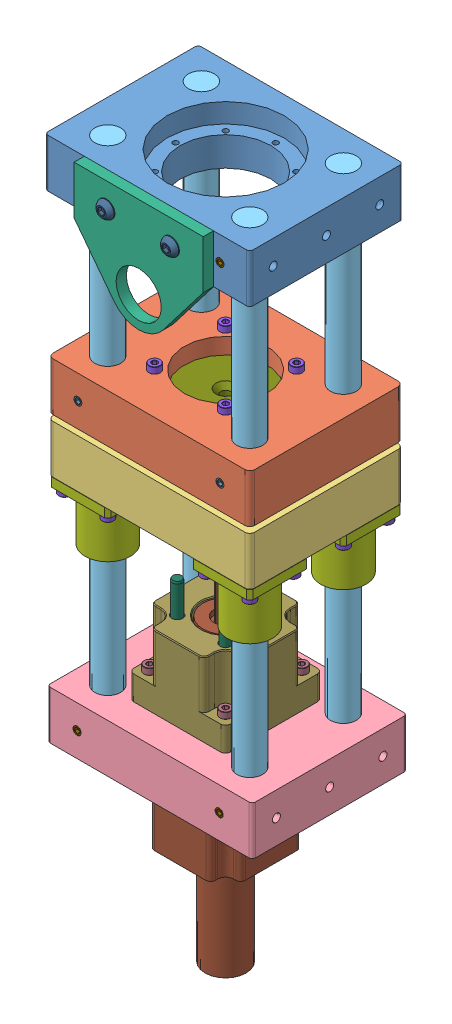
SolidWorks assembly 002 - Plate Assembly, configuration Default. Lengths in mm.
Overall size (129 435.72 106.38).
66 component instances, 16 part files, 53 mates.
Components (placement in the parent):
- 002-101 - Motor Plate-1: 002-101 - Motor Plate [Default] at (39.4552 68.0685 91.2976) size (127 30 95)
- 002-102 - Fixed Mold Plate-1: 002-102 - Fixed Mold Plate [Default] at (39.4552 -20.3315 91.2976) x (-1 0 0) z (0 0 1) size (125 30 95)
- 002-103 - Moving Mold Plate-1: 002-103 - Moving Mold Plate [Default] at (39.4552 -53.9039 91.2976) x (-1 0 0) z (0 0 1) size (125 30 95)
- 002-104 - Actuator Plate-1: 002-104 - Actuator Plate [Default] at (39.4552 -226.9315 91.2976) size (127 30 96)
- SP - 16x295mm Rail - Phidgets LMN4002_0-1: SP - 16x295mm Rail - Phidgets LMN4002_0 [Default] at (83.4552 -64.4315 120.2976) x (1 0 0) z (0 -1 0) size (16 16 325)
- 002-105 - Hopper Bracket-1: 002-105 - Hopper Bracket [Default] at (39.4552 83.0685 145.1476) x (1 0 0) z (0 1 0) size (80 6.35 69.95)
- SP - Bearing LMK16UU - Phidgets LMN4219_0-1: SP - Bearing LMK16UU - Phidgets LMN4219_0 [Default] at (83.4552 -83.9039 120.2976) x (0 0 -1) z (-1 0 0) size (37 37 37)
- SP - M4x12 SHCS - McMaster-Carr 91290A148-1: SP - M4x12 SHCS - McMaster-Carr 91290A148 [91290A148] at (96.8902 -77.9039 133.7326) x (1 0 0) z (0 1 0) size (7 7 16.33)
- SP - M4x12 SHCS - McMaster-Carr 91290A148-2: SP - M4x12 SHCS - McMaster-Carr 91290A148 [91290A148] at (96.8902 -77.9039 106.8626) x (1 0 0) z (0 1 0) size (7 7 16.33)
- SP - M4x12 SHCS - McMaster-Carr 91290A148-3: SP - M4x12 SHCS - McMaster-Carr 91290A148 [91290A148] at (70.0201 -77.9039 133.7326) x (1 0 0) z (0 1 0) size (7 7 16.33)
- SP - M4x12 SHCS - McMaster-Carr 91290A148-4: SP - M4x12 SHCS - McMaster-Carr 91290A148 [91290A148] at (70.0201 -77.9039 106.8626) x (1 0 0) z (0 1 0) size (7 7 16.33)
- SP - M6x10 CPSS - McMaster-Carr 91390A128-1: SP - M6x10 CPSS - McMaster-Carr 91390A128 [91390A128] at (83.4552 -211.9315 134.7915) size (6.22 6.16 11)
- SP - M6x10 CPSS - McMaster-Carr 91390A128-2: SP - M6x10 CPSS - McMaster-Carr 91390A128 [91390A128] at (83.4552 83.0685 134.2915) size (6.22 6.16 11)
- SP - M6x14 BHCS - McMaster-Carr 91239A319-1: SP - M6x14 BHCS - McMaster-Carr 91239A319 [91239A319] at (59.4552 83.0685 148.4476) size (10.5 10.5 17.89)
- SP - M6x14 BHCS - McMaster-Carr 91239A319-2: SP - M6x14 BHCS - McMaster-Carr 91239A319 [91239A319] at (19.4552 83.0685 148.4476) x (-1 0 0) z (0 0 1) size (10.5 10.5 17.89)
- SP - M6x10 CPSS - McMaster-Carr 91390A128-3: SP - M6x10 CPSS - McMaster-Carr 91390A128 [91390A128] at (-4.5448 83.0865 134.2915) x (-1 0 0) z (0 0 1) size (6.22 6.16 11)
- SP - Bearing LMK16UU - Phidgets LMN4219_0-2: SP - Bearing LMK16UU - Phidgets LMN4219_0 [Default] at (-4.5448 -83.9039 120.2976) x (0 0 -1) z (-1 0 0) size (37 37 37)
- SP - M4x12 SHCS - McMaster-Carr 91290A148-5: SP - M4x12 SHCS - McMaster-Carr 91290A148 [91290A148] at (-17.9799 -77.9039 133.7326) x (-1 0 0) z (0 1 0) size (7 7 16.33)
- SP - M4x12 SHCS - McMaster-Carr 91290A148-6: SP - M4x12 SHCS - McMaster-Carr 91290A148 [91290A148] at (-17.9799 -77.9039 106.8626) x (-1 0 0) z (0 1 0) size (7 7 16.33)
- SP - M4x12 SHCS - McMaster-Carr 91290A148-7: SP - M4x12 SHCS - McMaster-Carr 91290A148 [91290A148] at (8.8902 -77.9039 133.7326) x (-1 0 0) z (0 1 0) size (7 7 16.33)
- SP - M4x12 SHCS - McMaster-Carr 91290A148-8: SP - M4x12 SHCS - McMaster-Carr 91290A148 [91290A148] at (8.8902 -77.9039 106.8626) x (-1 0 0) z (0 1 0) size (7 7 16.33)
- SP - M6x10 CPSS - McMaster-Carr 91390A128-4: SP - M6x10 CPSS - McMaster-Carr 91390A128 [91390A128] at (-4.5448 -211.9135 134.7915) x (-1 0 0) z (0 0 1) size (6.22 6.16 11)
- SP - 16x295mm Rail - Phidgets LMN4002_0-2: SP - 16x295mm Rail - Phidgets LMN4002_0 [Default] at (-4.5448 -64.4315 120.2976) x (-1 0 0) z (0 1 0) size (16 16 325)
- SP - M4x12 SHCS - McMaster-Carr 91290A148-9: SP - M4x12 SHCS - McMaster-Carr 91290A148 [91290A148] at (63.0264 -219.9315 114.8688) x (1 0 0) z (0 1 0) size (7 7 16.33)
- SP - N23 Actuator - Haydon-Kerk 57M43-3_25-910-1: SP - N23 Actuator - Haydon-Kerk 57M43-3_25-910 [Default] at (39.4552 -226.9315 91.2976) x (1 0 0) z (0 1 0) size (56.4 56.4 266.25)
- 002-106 - Extractor Block-1: 002-106 - Extractor Block [Default] at (39.4552 -196.9315 91.2976) x (1 0 0) z (0 1 0) size (60 60 45)
- SP - M4x25 SHCS - McMaster-Carr 91290A176-1: SP - M4x25 SHCS - McMaster-Carr 91290A176 [91290A176] at (63.0264 -206.9315 114.8688) x (1 0 0) z (0 -1 0) size (7 7 29.41)
- SP - M6x8 SPSS - McMaster-Carr 94085A127-1: SP - M6x8 SPSS - McMaster-Carr 94085A127 [94085A127] at (83.4552 -35.3315 133.9976) size (6.21 6.18 10.6)
- SP - M6x8 SPSS - McMaster-Carr 94085A127-2: SP - M6x8 SPSS - McMaster-Carr 94085A127 [94085A127] at (-4.5448 -35.4104 133.9976) x (-1 0 0) z (0 0 1) size (6.21 6.18 10.6)
- SP - M4x12 SHCS - McMaster-Carr 91290A148-10: SP - M4x12 SHCS - McMaster-Carr 91290A148 [91290A148] at (15.884 -219.9315 114.8688) x (-1 0 0) z (0 1 0) size (7 7 16.33)
- SP - M4x25 SHCS - McMaster-Carr 91290A176-2: SP - M4x25 SHCS - McMaster-Carr 91290A176 [91290A176] at (15.884 -206.9315 114.8688) x (-1 0 0) z (0 -1 0) size (7 7 29.41)
- SP - M6x10 CPSS - McMaster-Carr 91390A128-5: SP - M6x10 CPSS - McMaster-Carr 91390A128 [91390A128] at (83.4552 83.0865 48.3037) x (1 0 0) z (0 0 -1) size (6.22 6.16 11)
- SP - Bearing LMK16UU - Phidgets LMN4219_0-3: SP - Bearing LMK16UU - Phidgets LMN4219_0 [Default] at (83.4552 -83.9039 62.2976) x (0 0 1) z (1 0 0) size (37 37 37)
- SP - M4x12 SHCS - McMaster-Carr 91290A148-11: SP - M4x12 SHCS - McMaster-Carr 91290A148 [91290A148] at (96.8902 -77.9039 48.8626) x (1 0 0) z (0 1 0) size (7 7 16.33)
- SP - M4x12 SHCS - McMaster-Carr 91290A148-12: SP - M4x12 SHCS - McMaster-Carr 91290A148 [91290A148] at (96.8902 -77.9039 75.7326) x (1 0 0) z (0 1 0) size (7 7 16.33)
- SP - M4x12 SHCS - McMaster-Carr 91290A148-13: SP - M4x12 SHCS - McMaster-Carr 91290A148 [91290A148] at (70.0201 -77.9039 48.8626) x (1 0 0) z (0 1 0) size (7 7 16.33)
- SP - M4x12 SHCS - McMaster-Carr 91290A148-14: SP - M4x12 SHCS - McMaster-Carr 91290A148 [91290A148] at (70.0201 -77.9039 75.7326) x (1 0 0) z (0 1 0) size (7 7 16.33)
- SP - M6x10 CPSS - McMaster-Carr 91390A128-6: SP - M6x10 CPSS - McMaster-Carr 91390A128 [91390A128] at (83.4552 -211.9135 47.8037) x (1 0 0) z (0 0 -1) size (6.22 6.16 11)
- SP - 16x295mm Rail - Phidgets LMN4002_0-3: SP - 16x295mm Rail - Phidgets LMN4002_0 [Default] at (83.4552 -64.4315 62.2976) x (1 0 0) z (0 1 0) size (16 16 325)
- SP - M6x8 SPSS - McMaster-Carr 94085A127-3: SP - M6x8 SPSS - McMaster-Carr 94085A127 [94085A127] at (83.4552 -35.4104 48.5976) x (1 0 0) z (0 0 -1) size (6.21 6.18 10.6)
- SP - M4x12 SHCS - McMaster-Carr 91290A148-15: SP - M4x12 SHCS - McMaster-Carr 91290A148 [91290A148] at (63.0264 -219.9315 67.7264) x (1 0 0) z (0 1 0) size (7 7 16.33)
- SP - M4x25 SHCS - McMaster-Carr 91290A176-3: SP - M4x25 SHCS - McMaster-Carr 91290A176 [91290A176] at (63.0264 -206.9315 67.7264) x (1 0 0) z (0 -1 0) size (7 7 29.41)
- SP - M6x10 CPSS - McMaster-Carr 91390A128-7: SP - M6x10 CPSS - McMaster-Carr 91390A128 [91390A128] at (-4.5448 83.0685 48.3037) x (-1 0 0) z (0 0 -1) size (6.22 6.16 11)
- SP - Bearing LMK16UU - Phidgets LMN4219_0-4: SP - Bearing LMK16UU - Phidgets LMN4219_0 [Default] at (-4.5448 -83.9039 62.2976) x (0 0 1) z (1 0 0) size (37 37 37)
- SP - M4x12 SHCS - McMaster-Carr 91290A148-16: SP - M4x12 SHCS - McMaster-Carr 91290A148 [91290A148] at (-17.9799 -77.9039 48.8626) x (-1 0 0) z (0 1 0) size (7 7 16.33)
- SP - M4x12 SHCS - McMaster-Carr 91290A148-17: SP - M4x12 SHCS - McMaster-Carr 91290A148 [91290A148] at (-17.9799 -77.9039 75.7326) x (-1 0 0) z (0 1 0) size (7 7 16.33)
- SP - M4x12 SHCS - McMaster-Carr 91290A148-18: SP - M4x12 SHCS - McMaster-Carr 91290A148 [91290A148] at (8.8902 -77.9039 48.8626) x (-1 0 0) z (0 1 0) size (7 7 16.33)
- SP - M4x12 SHCS - McMaster-Carr 91290A148-19: SP - M4x12 SHCS - McMaster-Carr 91290A148 [91290A148] at (8.8902 -77.9039 75.7326) x (-1 0 0) z (0 1 0) size (7 7 16.33)
- SP - M6x10 CPSS - McMaster-Carr 91390A128-8: SP - M6x10 CPSS - McMaster-Carr 91390A128 [91390A128] at (-4.5448 -211.9315 47.8037) x (-1 0 0) z (0 0 -1) size (6.22 6.16 11)
- SP - 16x295mm Rail - Phidgets LMN4002_0-4: SP - 16x295mm Rail - Phidgets LMN4002_0 [Default] at (-4.5448 -64.4315 62.2976) x (-1 0 0) z (0 -1 0) size (16 16 325)
- SP - M6x8 SPSS - McMaster-Carr 94085A127-4: SP - M6x8 SPSS - McMaster-Carr 94085A127 [94085A127] at (-4.5448 -35.3315 48.5976) x (-1 0 0) z (0 0 -1) size (6.21 6.18 10.6)
- SP - M4x12 SHCS - McMaster-Carr 91290A148-20: SP - M4x12 SHCS - McMaster-Carr 91290A148 [91290A148] at (15.884 -219.9315 67.7264) x (-1 0 0) z (0 1 0) size (7 7 16.33)
- SP - M4x25 SHCS - McMaster-Carr 91290A176-4: SP - M4x25 SHCS - McMaster-Carr 91290A176 [91290A176] at (15.884 -206.9315 67.7264) x (-1 0 0) z (0 -1 0) size (7 7 29.41)
- SP - M6x40 DWL - McMaster-Carr 91585A692-1: SP - M6x40 DWL - McMaster-Carr 91585A692 [91585A692] at (54.4552 -151.9315 106.2976) x (0 -1 0) z (0.987577 0 -0.157135) size (40 6 6)
- SP - M6x40 DWL - McMaster-Carr 91585A692-2: SP - M6x40 DWL - McMaster-Carr 91585A692 [91585A692] at (24.4552 -151.9315 106.2976) x (0 -1 0) z (0.987577 0 0.157135) size (40 6 6)
- SP - M6x40 DWL - McMaster-Carr 91585A692-3: SP - M6x40 DWL - McMaster-Carr 91585A692 [91585A692] at (54.4552 -151.9315 76.2976) x (0 -1 0) z (-0.987577 0 -0.157135) size (40 6 6)
- SP - M6x40 DWL - McMaster-Carr 91585A692-4: SP - M6x40 DWL - McMaster-Carr 91585A692 [91585A692] at (24.4552 -151.9315 76.2976) x (0 -1 0) z (-0.987577 0 0.157135) size (40 6 6)
- SP - M4x12 SHCS - McMaster-Carr 91290A148-22: SP - M4x12 SHCS - McMaster-Carr 91290A148 [91290A148] at (61.4552 -71.9039 113.2976) x (1 0 0) z (0 1 0) size (7 7 16.33)
- SP - M4x12 SHCS - McMaster-Carr 91290A148-23: SP - M4x12 SHCS - McMaster-Carr 91290A148 [91290A148] at (61.4552 -32.3315 113.2976) x (0.973251 0 0.229745) z (0 -1 0) size (7 7 16.33)
- SP - M4x12 SHCS - McMaster-Carr 91290A148-24: SP - M4x12 SHCS - McMaster-Carr 91290A148 [91290A148] at (17.4552 -32.3315 113.2976) x (-0.973251 0 0.229745) z (0 -1 0) size (7 7 16.33)
- SP - M4x12 SHCS - McMaster-Carr 91290A148-25: SP - M4x12 SHCS - McMaster-Carr 91290A148 [91290A148] at (17.4552 -71.9039 113.2976) x (-1 0 0) z (0 1 0) size (7 7 16.33)
- SP - M4x12 SHCS - McMaster-Carr 91290A148-26: SP - M4x12 SHCS - McMaster-Carr 91290A148 [91290A148] at (61.4552 -71.9039 69.2976) x (1 0 0) z (0 1 0) size (7 7 16.33)
- SP - M4x12 SHCS - McMaster-Carr 91290A148-27: SP - M4x12 SHCS - McMaster-Carr 91290A148 [91290A148] at (17.4552 -71.9039 69.2976) x (-1 0 0) z (0 1 0) size (7 7 16.33)
- SP - M4x12 SHCS - McMaster-Carr 91290A148-28: SP - M4x12 SHCS - McMaster-Carr 91290A148 [91290A148] at (61.4552 -32.3315 69.2976) x (0.973251 0 -0.229745) z (0 -1 0) size (7 7 16.33)
- SP - M4x12 SHCS - McMaster-Carr 91290A148-29: SP - M4x12 SHCS - McMaster-Carr 91290A148 [91290A148] at (17.4552 -32.3315 69.2976) x (-0.973251 0 -0.229745) z (0 -1 0) size (7 7 16.33)
- 002-107 - Blank Mold Cavity-1: 002-107 - Blank Mold Cavity [Default] at (39.4552 -30.3315 91.2976) x (1 0 0) z (0 -1 0) size (60 60 22)
Mates (geometry in assembly coordinates):
- Concentric1: concentric anti-aligned: cylinder of 002-101 - Motor Plate-1 through (-4.5448 98.0685 120.2976) axis (0 -1 0) radius 8; cylinder of 002-102 - Fixed Mold Plate-1 through (-4.5448 -50.3315 120.2976) axis (0 1 0) radius 8
- Coincident2: coincident aligned: plane of 002-101 - Motor Plate-1 through (39.4552 98.0685 138.7976) normal (0 0 1); plane of 002-102 - Fixed Mold Plate-1 through (101.9552 -50.3315 138.7976) normal (0 0 1)
- Concentric2: concentric anti-aligned: cylinder of 002-101 - Motor Plate-1 through (83.4552 98.0685 120.2976) axis (0 -1 0) radius 8; cylinder of 002-102 - Fixed Mold Plate-1 through (83.4552 -50.3315 120.2976) axis (0 1 0) radius 8
- Concentric3: concentric aligned: cylinder of 002-102 - Fixed Mold Plate-1 through (-4.5448 -50.3315 120.2976) axis (0 1 0) radius 8; cylinder of 002-103 - Moving Mold Plate-1 through (-4.5448 -83.9039 120.2976) axis (0 1 0) radius 8.5
- Concentric4: concentric aligned: cylinder of 002-102 - Fixed Mold Plate-1 through (83.4552 -50.3315 120.2976) axis (0 1 0) radius 8; cylinder of 002-103 - Moving Mold Plate-1 through (83.4552 -83.9039 120.2976) axis (0 1 0) radius 8.5
- Concentric5: concentric anti-aligned: cylinder of 002-103 - Moving Mold Plate-1 through (83.4552 -83.9039 120.2976) axis (0 1 0) radius 8.5; cylinder of 002-104 - Actuator Plate-1 through (83.4552 -196.9315 120.2976) axis (0 -1 0) radius 8
- Concentric6: concentric anti-aligned: cylinder of 002-103 - Moving Mold Plate-1 through (83.4552 -83.9039 62.2976) axis (0 1 0) radius 8.5; cylinder of 002-104 - Actuator Plate-1 through (83.4552 -196.9315 62.2976) axis (0 -1 0) radius 8
- Coincident4: coincident anti-aligned: plane of 002-101 - Motor Plate-1 through (39.4552 98.0685 138.7976) normal (0 0 1); plane of 002-105 - Hopper Bracket-1 through (39.4552 83.0685 138.7976) normal (0 0 -1)
- Concentric7: concentric anti-aligned: cylinder of 002-101 - Motor Plate-1 through (59.4552 83.0685 138.7976) axis (0 0 1) radius 2.5; cylinder of 002-105 - Hopper Bracket-1 through (59.4552 83.0685 138.7976) axis (0 0 -1) radius 3.3
- Concentric8: concentric anti-aligned: cylinder of 002-101 - Motor Plate-1 through (19.4552 83.0685 138.7976) axis (0 0 1) radius 2.5; cylinder of 002-105 - Hopper Bracket-1 through (19.4552 83.0685 138.7976) axis (0 0 -1) radius 3.3
- Concentric9: concentric anti-aligned: cylinder of 002-101 - Motor Plate-1 through (83.4552 98.0685 120.2976) axis (0 -1 0) radius 8; cylinder of SP - 16x295mm Rail - Phidgets LMN4002_0-1 through (83.4552 -226.9315 120.2976) axis (0 1 0) radius 8
- Coincident5: coincident aligned: plane of 002-101 - Motor Plate-1 through (39.4552 98.0685 91.2976) normal (0 1 0); plane of SP - 16x295mm Rail - Phidgets LMN4002_0-1 through (83.4552 98.0685 120.2976) normal (0 1 0)
- Coincident6: coincident aligned: plane of 002-104 - Actuator Plate-1 through (39.4552 -226.9315 91.2976) normal (0 -1 0); plane of SP - 16x295mm Rail - Phidgets LMN4002_0-1 through (83.4552 -226.9315 120.2976) normal (0 -1 0)
- Concentric10: concentric aligned: cylinder of SP - 16x295mm Rail - Phidgets LMN4002_0-1 through (83.4552 -226.9315 120.2976) axis (0 1 0) radius 8; cylinder of SP - Bearing LMK16UU - Phidgets LMN4219_0-1 through (83.4552 -83.9039 120.2976) axis (0 1 0) radius 14
- Concentric11: concentric anti-aligned: cylinder of 002-103 - Moving Mold Plate-1 through (96.8902 -83.9039 133.7326) axis (0 -1 0) radius 1.65; cylinder of SP - Bearing LMK16UU - Phidgets LMN4219_0-1 through (96.8902 -120.9039 133.7326) axis (0 1 0) radius 2.25
- Coincident7: coincident anti-aligned: plane of 002-103 - Moving Mold Plate-1 through (39.4552 -83.9039 91.2976) normal (0 -1 0); plane of SP - Bearing LMK16UU - Phidgets LMN4219_0-1 through (96.9552 -83.9039 120.2976) normal (0 1 0)
- Concentric12: concentric aligned: cylinder of SP - Bearing LMK16UU - Phidgets LMN4219_0-1 through (96.8902 -120.9039 133.7326) axis (0 1 0) radius 2.25; cylinder of SP - M4x12 SHCS - McMaster-Carr 91290A148-1 through (96.8902 -93.9039 133.7326) axis (0 1 0) radius 3.5
- Coincident8: coincident anti-aligned: plane of SP - Bearing LMK16UU - Phidgets LMN4219_0-1 through (83.4552 -89.9039 120.2976) normal (0 -1 0); plane of SP - M4x12 SHCS - McMaster-Carr 91290A148-1 through (96.8902 -89.9039 133.7326) normal (0 1 0)
- Concentric13: concentric aligned: cylinder of SP - Bearing LMK16UU - Phidgets LMN4219_0-1 through (96.8902 -120.9039 106.8626) axis (0 1 0) radius 2.25; cylinder of SP - M4x12 SHCS - McMaster-Carr 91290A148-2 through (96.8902 -93.9039 106.8626) axis (0 1 0) radius 3.5
- Coincident9: coincident anti-aligned: plane of SP - Bearing LMK16UU - Phidgets LMN4219_0-1 through (83.4552 -89.9039 120.2976) normal (0 -1 0); plane of SP - M4x12 SHCS - McMaster-Carr 91290A148-2 through (96.8902 -89.9039 106.8626) normal (0 1 0)
- Concentric14: concentric aligned: cylinder of SP - Bearing LMK16UU - Phidgets LMN4219_0-1 through (70.0201 -120.9039 133.7326) axis (0 1 0) radius 2.25; cylinder of SP - M4x12 SHCS - McMaster-Carr 91290A148-3 through (70.0201 -93.9039 133.7326) axis (0 1 0) radius 3.5
- Coincident10: coincident anti-aligned: plane of SP - Bearing LMK16UU - Phidgets LMN4219_0-1 through (83.4552 -89.9039 120.2976) normal (0 -1 0); plane of SP - M4x12 SHCS - McMaster-Carr 91290A148-3 through (70.0201 -89.9039 133.7326) normal (0 1 0)
- Concentric15: concentric aligned: cylinder of SP - Bearing LMK16UU - Phidgets LMN4219_0-1 through (70.0201 -120.9039 106.8626) axis (0 1 0) radius 2.25; cylinder of SP - M4x12 SHCS - McMaster-Carr 91290A148-4 through (70.0201 -93.9039 106.8626) axis (0 1 0) radius 3.5
- Coincident11: coincident anti-aligned: plane of SP - Bearing LMK16UU - Phidgets LMN4219_0-1 through (83.4552 -89.9039 120.2976) normal (0 -1 0); plane of SP - M4x12 SHCS - McMaster-Carr 91290A148-4 through (70.0201 -89.9039 106.8626) normal (0 1 0)
- Coincident12: coincident aligned: plane of 002-104 - Actuator Plate-1 through (-23.0448 -196.9315 139.2976) normal (0 0 1); plane of SP - M6x10 CPSS - McMaster-Carr 91390A128-1 through (83.4552 -211.9315 139.2976) normal (0 0 1)
- Concentric16: concentric aligned: cylinder of 002-104 - Actuator Plate-1 through (83.4552 -211.9315 139.2976) axis (0 0 1) radius 2.5; cylinder of SP - M6x10 CPSS - McMaster-Carr 91390A128-1 through (83.4552 -211.9315 130.2853) axis (0 0 1) radius 3
- Concentric17: concentric aligned: cylinder of 002-101 - Motor Plate-1 through (83.4552 83.0685 138.7976) axis (0 0 1) radius 2.5; cylinder of SP - M6x10 CPSS - McMaster-Carr 91390A128-2 through (83.4552 83.0685 129.7853) axis (0 0 1) radius 3
- Coincident13: coincident aligned: plane of 002-101 - Motor Plate-1 through (39.4552 98.0685 138.7976) normal (0 0 1); plane of SP - M6x10 CPSS - McMaster-Carr 91390A128-2 through (83.4552 83.0685 138.7976) normal (0 0 1)
- Concentric18: concentric anti-aligned: cylinder of 002-101 - Motor Plate-1 through (59.4552 83.0685 138.7976) axis (0 0 1) radius 2.5; cylinder of SP - M6x14 BHCS - McMaster-Carr 91239A319-1 through (59.4552 83.0685 131.1476) axis (0 0 -1) radius 3
- Coincident14: coincident anti-aligned: plane of 002-105 - Hopper Bracket-1 through (39.4552 83.0685 145.1476) normal (0 0 1); plane of SP - M6x14 BHCS - McMaster-Carr 91239A319-1 through (59.4552 77.8185 145.1476) normal (0 0 -1)
- Concentric19: concentric aligned: cylinder of 002-104 - Actuator Plate-1 through (39.4552 -196.9315 91.2976) axis (0 -1 0) radius 19.1; cylinder of SP - N23 Actuator - Haydon-Kerk 57M43-3_25-910-1 through (39.4552 -225.4315 91.2976) axis (0 -1 0) radius 19.0754
- Concentric20: concentric aligned: cylinder of 002-104 - Actuator Plate-1 through (63.0264 -196.9315 114.8688) axis (0 1 0) radius 1.65; cylinder of SP - N23 Actuator - Haydon-Kerk 57M43-3_25-910-1 through (63.0264 -231.9315 114.8688) axis (0 1 0) radius 2.6
- Coincident15: coincident anti-aligned: plane of 002-104 - Actuator Plate-1 through (39.4552 -226.9315 91.2976) normal (0 -1 0); plane of SP - N23 Actuator - Haydon-Kerk 57M43-3_25-910-1 through (11.2552 -226.9315 119.4976) normal (0 1 0)
- Concentric21: concentric aligned: cylinder of SP - M4x12 SHCS - McMaster-Carr 91290A148-9 through (63.0264 -235.9315 114.8688) axis (0 1 0) radius 3.5; cylinder of SP - N23 Actuator - Haydon-Kerk 57M43-3_25-910-1 through (63.0264 -231.9315 114.8688) axis (0 1 0) radius 2.6
- Coincident16: coincident anti-aligned: plane of SP - M4x12 SHCS - McMaster-Carr 91290A148-9 through (63.0264 -231.9315 114.8688) normal (0 1 0); plane of SP - N23 Actuator - Haydon-Kerk 57M43-3_25-910-1 through (55.285 -231.9315 119.4976) normal (0 -1 0)
- Concentric22: concentric anti-aligned: cylinder of 002-104 - Actuator Plate-1 through (39.4552 -196.9315 91.2976) axis (0 -1 0) radius 19.1; cylinder of 002-106 - Extractor Block-1 through (39.4552 -196.9315 91.2976) axis (0 1 0) radius 15
- Concentric23: concentric aligned: cylinder of 002-104 - Actuator Plate-1 through (63.0264 -196.9315 114.8688) axis (0 1 0) radius 1.65; cylinder of 002-106 - Extractor Block-1 through (63.0264 -181.9315 114.8688) axis (0 1 0) radius 2.25
- Coincident17: coincident anti-aligned: plane of 002-104 - Actuator Plate-1 through (39.4552 -196.9315 91.2976) normal (0 1 0); plane of 002-106 - Extractor Block-1 through (39.4552 -196.9315 91.2976) normal (0 -1 0)
- Concentric24: concentric anti-aligned: cylinder of 002-106 - Extractor Block-1 through (63.0264 -181.9315 114.8688) axis (0 1 0) radius 2.25; cylinder of SP - M4x25 SHCS - McMaster-Carr 91290A176-1 through (63.0264 -177.9315 114.8688) axis (0 -1 0) radius 3.5
- Coincident18: coincident anti-aligned: plane of 002-106 - Extractor Block-1 through (39.4552 -181.9315 91.2976) normal (0 1 0); plane of SP - M4x25 SHCS - McMaster-Carr 91290A176-1 through (63.0264 -181.9315 114.8688) normal (0 -1 0)
- Concentric25: concentric anti-aligned: cylinder of 002-102 - Fixed Mold Plate-1 through (83.4552 -35.3315 138.7976) axis (0 0 1) radius 2.5; cylinder of SP - M6x8 SPSS - McMaster-Carr 94085A127-1 through (83.4552 -35.3315 129.1976) axis (0 0 -1) radius 3
- Coincident19: coincident aligned: plane of 002-102 - Fixed Mold Plate-1 through (101.9552 -50.3315 138.7976) normal (0 0 1); plane of SP - M6x8 SPSS - McMaster-Carr 94085A127-1 through (83.4552 -35.3315 138.7976) normal (0 0 1)
- Concentric27: concentric anti-aligned: cylinder of 002-106 - Extractor Block-1 through (54.4552 -171.9315 106.2976) axis (0 1 0) radius 3; cylinder of SP - M6x40 DWL - McMaster-Carr 91585A692-1 through (54.4552 -133.1315 106.2976) axis (0 -1 0) radius 3
- Coincident20: coincident anti-aligned: plane of 002-106 - Extractor Block-1 through (54.4552 -171.9315 106.2976) normal (0 1 0); plane of SP - M6x40 DWL - McMaster-Carr 91585A692-1 through (54.4552 -171.9315 106.2976) normal (0 -1 0)
- Coincident21: coincident anti-aligned: plane of 002-103 - Moving Mold Plate-1 through (39.4552 -83.9039 91.2976) normal (0 -1 0); plane of SP - M4x12 SHCS - McMaster-Carr 91290A148-22 through (61.4552 -83.9039 113.2976) normal (0 1 0)
- Concentric28: concentric aligned: cylinder of 002-103 - Moving Mold Plate-1 through (61.4552 -73.9039 113.2976) axis (0 1 0) radius 2.25; cylinder of SP - M4x12 SHCS - McMaster-Carr 91290A148-22 through (61.4552 -87.9039 113.2976) axis (0 1 0) radius 3.5
- Concentric29: concentric aligned: cylinder of 002-102 - Fixed Mold Plate-1 through (61.4552 -50.3315 113.2976) axis (0 -1 0) radius 2.25; cylinder of SP - M4x12 SHCS - McMaster-Carr 91290A148-23 through (61.4552 -16.3315 113.2976) axis (0 -1 0) radius 3.5
- Coincident22: coincident anti-aligned: plane of 002-102 - Fixed Mold Plate-1 through (39.4552 -20.3315 91.2976) normal (0 1 0); plane of SP - M4x12 SHCS - McMaster-Carr 91290A148-23 through (61.4552 -20.3315 113.2976) normal (0 -1 0)
- Concentric30: concentric anti-aligned: cylinder of 002-102 - Fixed Mold Plate-1 through (61.4552 -50.3315 113.2976) axis (0 -1 0) radius 2.25; cylinder of 002-107 - Blank Mold Cavity-1 through (61.4552 -30.3315 113.2976) axis (0 1 0) radius 1.65
- Concentric31: concentric anti-aligned: cylinder of 002-102 - Fixed Mold Plate-1 through (17.4552 -50.3315 113.2976) axis (0 -1 0) radius 2.25; cylinder of 002-107 - Blank Mold Cavity-1 through (17.4552 -30.3315 113.2976) axis (0 1 0) radius 1.65
- Coincident23: coincident anti-aligned: plane of 002-102 - Fixed Mold Plate-1 through (39.4552 -30.3315 91.2976) normal (0 -1 0); plane of 002-107 - Blank Mold Cavity-1 through (39.4552 -30.3315 91.2976) normal (0 1 0)
- Distance1: distance = 118.4 mm aligned: plane of 002-102 - Fixed Mold Plate-1 through (39.4552 -20.3315 91.2976) normal (0 1 0); plane of 002-101 - Motor Plate-1 through (39.4552 98.0685 91.2976) normal (0 1 0)
- Coincident25: coincident anti-aligned: plane of 002-103 - Moving Mold Plate-1 through (39.4552 -83.9039 91.2976) normal (0 -1 0); plane of SP - N23 Actuator - Haydon-Kerk 57M43-3_25-910-1 through (45.8814 -83.9039 97.7238) normal (0 1 0)
